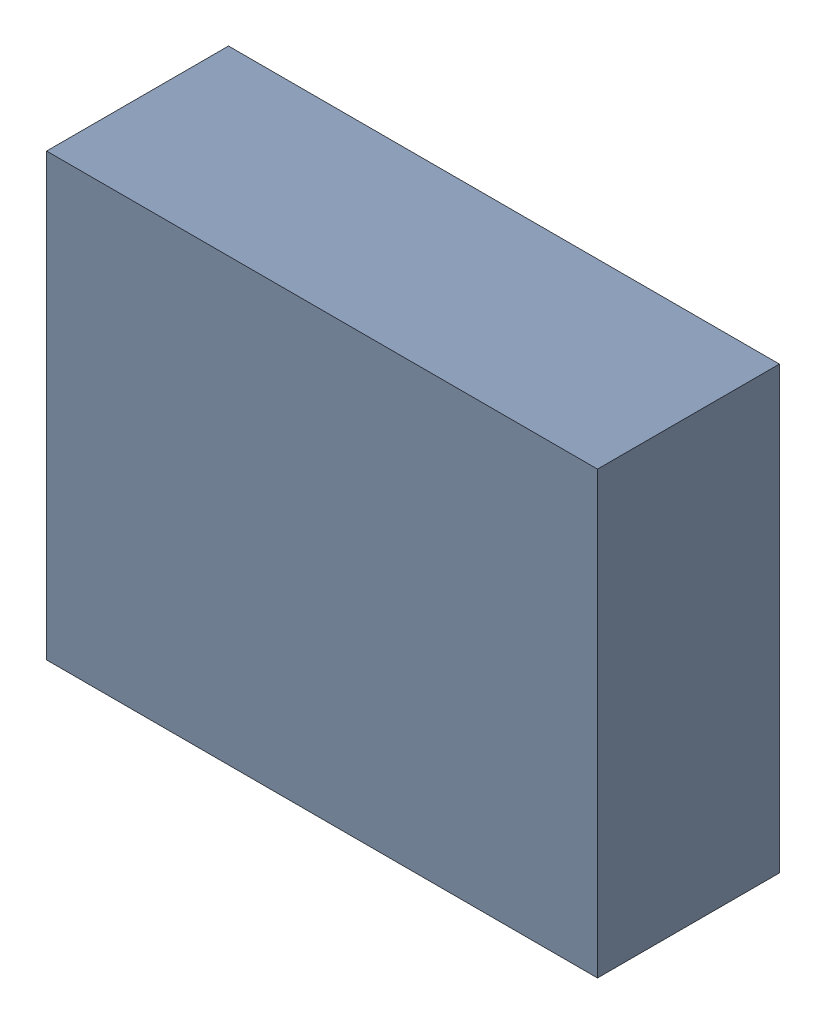
SolidWorks assembly USB45_U2, configuration Default. Lengths in mm.
Overall size (5 4 1.65).
2 component instances, 1 part files, 0 mates.
Components (placement in the parent):
- 402662544-1: 402662544 [Default] at (156.845 36.83 -2.8544) size (5 4 1.65)
  - Extruded_29-1: Extruded_29 [Default] at origin size (5 4 1.65)
